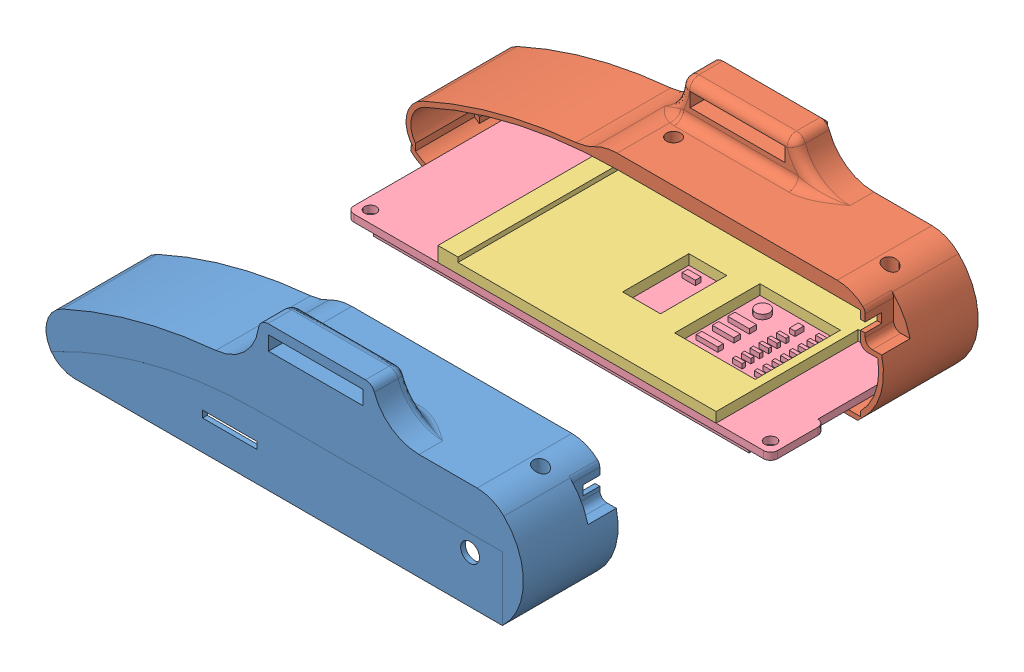
SolidWorks assembly P4.2_CASE, configuration Default. Lengths in mm.
Overall size (122.26 48.76 98.04).
4 component instances, 4 part files, 9 mates.
Components (placement in the parent):
- P4.1_CASE_LEFT-1: P4.1_CASE_LEFT [Default] at origin size (100.85 31.49 20)
- P4.1_CASE_RIGHT-1: P4.1_CASE_RIGHT [Default] at (0 0 -56.0445) size (122.26 48.76 22)
- P4.1_SPACER-1: P4.1_SPACER [Default] at (4.1742 -38.4206 -56.0445) x (0 0 1) z (-1 0 0) size (38 3.13 70.25)
- P4_2.9_EPD-1: P4_2.9_EPD [Default] at (93.6716 -38.4194 -56.0445) x (0 0 1) z (1 0 0) size (38 3.55 89.5)
Mates (geometry in assembly coordinates):
- Coincident1: coincident anti-aligned: plane of P4.1_CASE_RIGHT-1 through (3.6742 -34.9694 -56.0445) normal (0 0 1); plane of P4.1_SPACER-1 through (23.4242 -36.2906 -56.0445) normal (0 0 -1)
- Concentric1: concentric aligned: cylinder of P4.1_CASE_RIGHT-1 through (91.1742 -37.9694 -53.5445) axis (0 -1 0) radius 1.25; cylinder of P4.1_SPACER-1 through (91.1742 -36.2906 -53.5445) axis (0 -1 0) radius 1.25
- Coincident2: coincident aligned: plane of P4.1_CASE_LEFT-1 through (42.6716 -18.4794 -52.4203) normal (0 1 0); plane of P4.1_CASE_RIGHT-1 through (42.6716 -18.4794 -108.4648) normal (0 1 0)
- Coincident3: coincident aligned: plane of P4.1_CASE_LEFT-1 through (80.0742 -40.9694 3) normal (-0.707107 -0.707107 0); plane of P4.1_CASE_RIGHT-1 through (80.0742 -40.9694 -53.0445) normal (-0.707107 -0.707107 0)
- LimitDistance1: limit distance = 56.0445 mm anti-aligned: plane of P4.1_CASE_RIGHT-1 through (0 0 -37.0445) normal (0 0 1); plane of P4.1_CASE_LEFT-1 through (0 0 19) normal (0 0 -1)
- Coincident4: coincident anti-aligned: plane of P4.1_CASE_RIGHT-1 through (21.0292 -40.9694 -18.0445) normal (0 1 0); plane of P4_2.9_EPD-1 through (93.6716 -40.9694 -56.0445) normal (0 -1 0)
- Coincident5: coincident anti-aligned: plane of P4.1_CASE_RIGHT-1 through (93.6716 0 -18.0445) normal (-1 0 0); plane of P4_2.9_EPD-1 through (93.6716 -39.9194 -28.0445) normal (1 0 0)
- Coincident6: coincident anti-aligned: plane of P4.1_CASE_RIGHT-1 through (3.6742 -34.9694 -56.0445) normal (0 0 1); plane of P4_2.9_EPD-1 through (92.1716 -39.9194 -56.0445) normal (0 0 -1)
- Distance1: distance = 1 mm anti-aligned: plane of P4.1_SPACER-1 through (92.1742 -36.2906 -19.5445) normal (0 1 0); plane of P4.1_CASE_RIGHT-1 through (45.7932 -35.2906 -55.0445) normal (0 -1 0)
